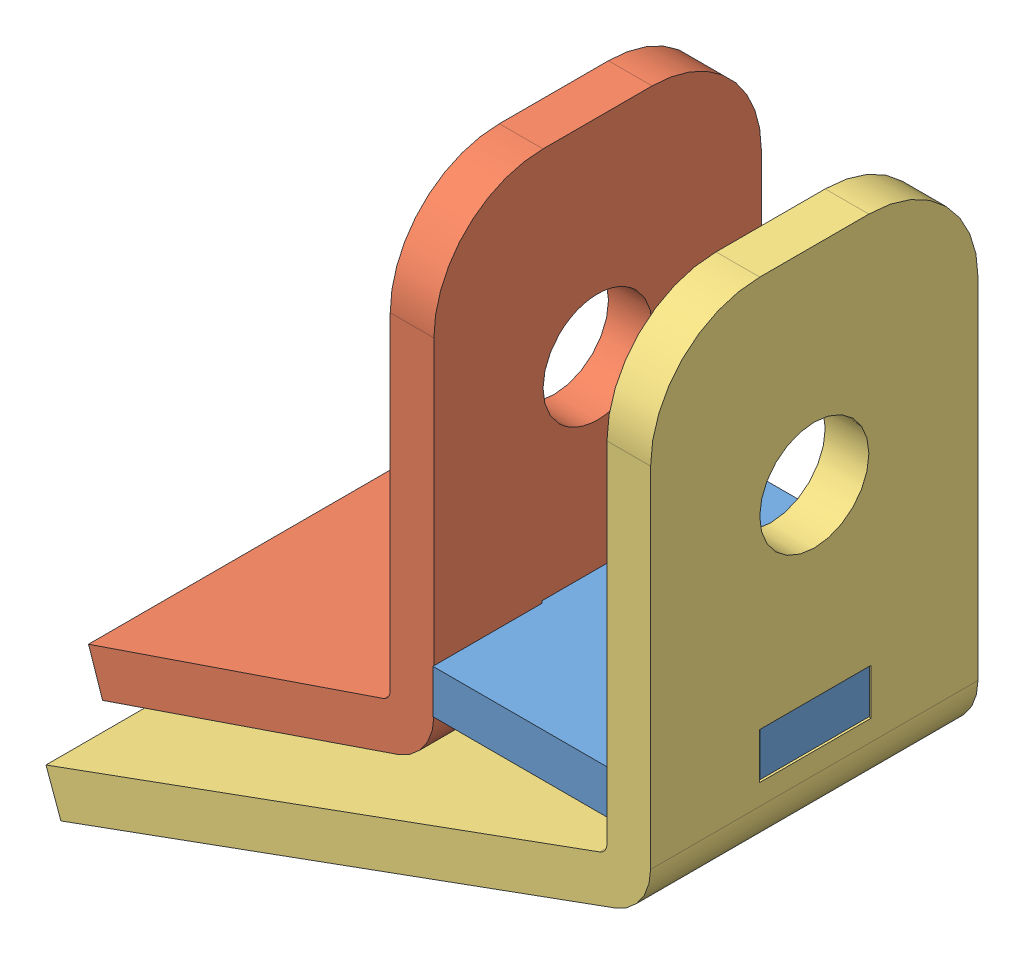
SolidWorks assembly PUTM-F-FR-MT-Aero-FW- Upper-Mounting, configuration Domyślna. Lengths in mm.
Overall size (27.7 32.64 15.07).
3 component instances, 3 part files, 6 mates.
Components (placement in the parent):
- PUTM-F-FR-MT-Aero-FW- Upper-Mounting-Part 3-1: PUTM-F-FR-MT-Aero-FW- Upper-Mounting-Part 3 [Domyślna] at (-15.8581 365.2905 33.8829) size (12 2 15)
- PUTM-F-FR-MT-Aero-FW- Upper-Mounting.Part2-2: PUTM-F-FR-MT-Aero-FW- Upper-Mounting.Part2 [Domyślna] at (-15.8575 365.2905 33.8357) size (15.83 26.97 15)
- PUTM-F-FR-MT-Aero-FW- Upper-Mounting-Part1-1: PUTM-F-FR-MT-Aero-FW- Upper-Mounting-Part1 [Domyślna] at (-15.8581 365.2387 33.9051) size (27.7 32.59 15)
Mates (geometry in assembly coordinates):
- Wspólnie5: coincident anti-aligned: plane of mocowanie gora 3^Złożenie3-1 through (-25.8581 -10.0296 28.8829) normal (0 0 1); plane of Left sidePUTM-F-FR-MT-Aero-FW- Upper-Mounting.Part2-2 through (-10.8575 -10.0296 28.8829) normal (0 0 -1)
- Wspólnie6: coincident anti-aligned: plane of mocowanie gora 3^Złożenie3-1 through (-23.8581 -10.0296 18.8829) normal (0 -1 0); plane of Left sidePUTM-F-FR-MT-Aero-FW- Upper-Mounting.Part2-2 through (-10.8575 -10.0296 23.7875) normal (0 1 0)
- Zablokuj1: lock: unknown of Left sidePUTM-F-FR-MT-Aero-FW- Upper-Mounting-Part 3-1; unknown of Left sidePUTM-F-FR-MT-Aero-FW- Upper-Mounting.Part2-2
- Wspólnie9: coincident anti-aligned: plane of mocowanie gora 3^Złożenie3-1 through (-15.8581 -8.0343 18.8829) normal (1 0 0); plane of mocowanie gora ^Złożenie1-1 through (-15.8581 -10.0814 18.9051) normal (-1 0 0)
- Wspólnie10: coincident anti-aligned: plane of mocowanie gora 3^Złożenie3-1 through (-15.8581 -8.0343 18.8829) normal (0 1 0); plane of mocowanie gora ^Złożenie1-1 through (-28.8581 -8.0343 23.8051) normal (0 -1 0)
- Zablokuj3: lock: unknown of Left sidePUTM-F-FR-MT-Aero-FW- Upper-Mounting-Part 3-1; unknown of Left sidePUTM-F-FR-MT-Aero-FW- Upper-Mounting-Part1-1
